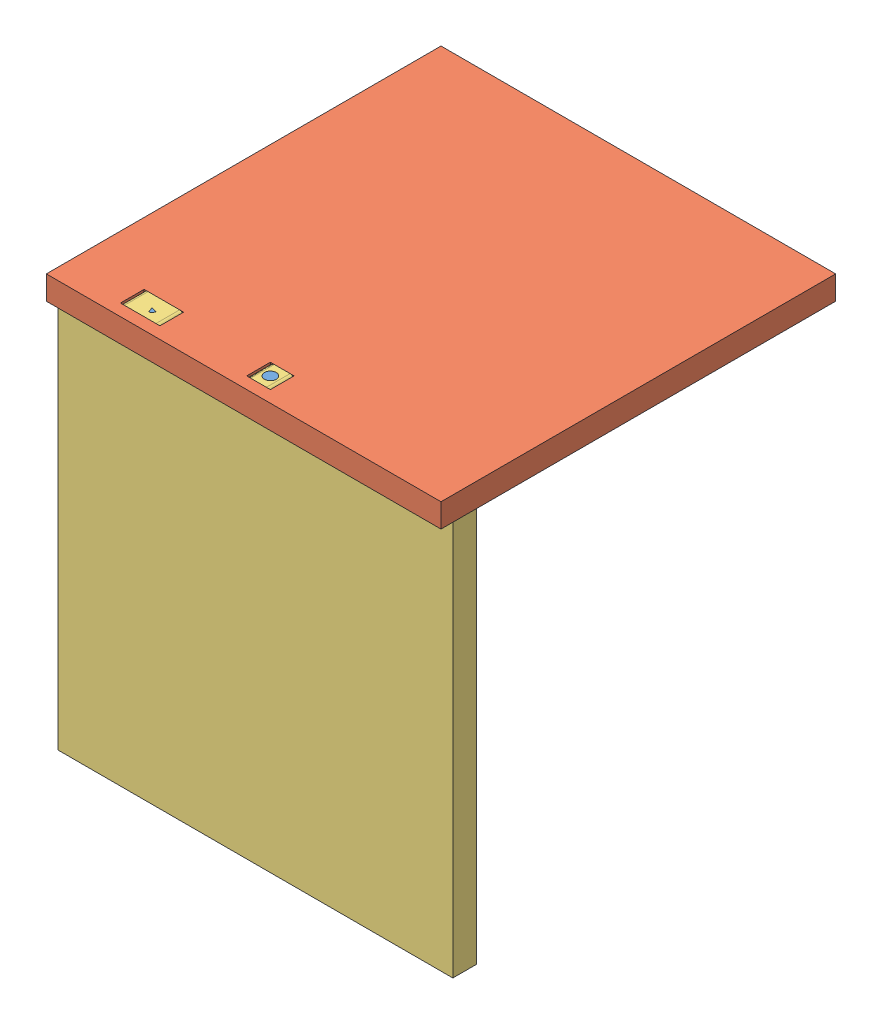
SolidWorks assembly tab_slot, configuration narrow. Lengths in mm.
Overall size (100 106 100).
4 component instances, 3 part files, 10 mates.
Components (placement in the parent):
- virtual_pin-1: virtual_pin [Default] at (0.7678 6 44) size (3 10 3)
- Part2-1: Part2 [Default] at origin size (100 6 100)
- Part3-1: Part3 [Default] at (0 -50 47) x (1 0 0) z (0 1 0) size (100 6 106)
- virtual_pin-3: virtual_pin [Default] at (-29.2132 6 44) x (-1 0 0) z (0 0 -1) size (3 10 3)
Mates (geometry in assembly coordinates):
- Coincident2: coordinate: point of Part2-1; point of assembly
- Coincident3: coincident anti-aligned: plane of Part2-1 through (0 0 0) normal (0 -1 0); plane of Part3-1 through (-50 0 41) normal (0 1 0)
- Coincident4: coincident aligned: plane of Part2-1 through (50 6 -50) normal (1 0 0); plane of Part3-1 through (50 -100 41) normal (1 0 0)
- Distance2: distance = 3 mm aligned: plane of Part3-1 through (0 -50 47) normal (0 0 1); plane of Part2-1 through (-50 6 50) normal (0 0 1)
- Coincident7: coincident: line of virtual_pin-1 through (0.7678 61 44) axis (0 -1 0); point of Part2-1
- Coincident6: coincident aligned: plane of virtual_pin-1 through (0.7678 6 44) normal (0 1 0); plane of Part2-1 through (0 6 0) normal (0 1 0)
- Parallel1: parallel aligned: plane of virtual_pin-1 through (0.7678 6 44) normal (1 0 0); plane of Part2-1 through (50 6 -50) normal (1 0 0)
- Coincident12: coincident: point of Part2-1; line of virtual_pin-3 through (-29.2132 61 44) axis (0 -1 0)
- Coincident13: coincident aligned: plane of Part2-1 through (0 6 0) normal (0 1 0); plane of virtual_pin-3
- Parallel3: parallel aligned: plane of Part2-1 through (-50 6 -50) normal (-1 0 0); plane of virtual_pin-3 through (-29.2132 6 44) normal (-1 0 0)
